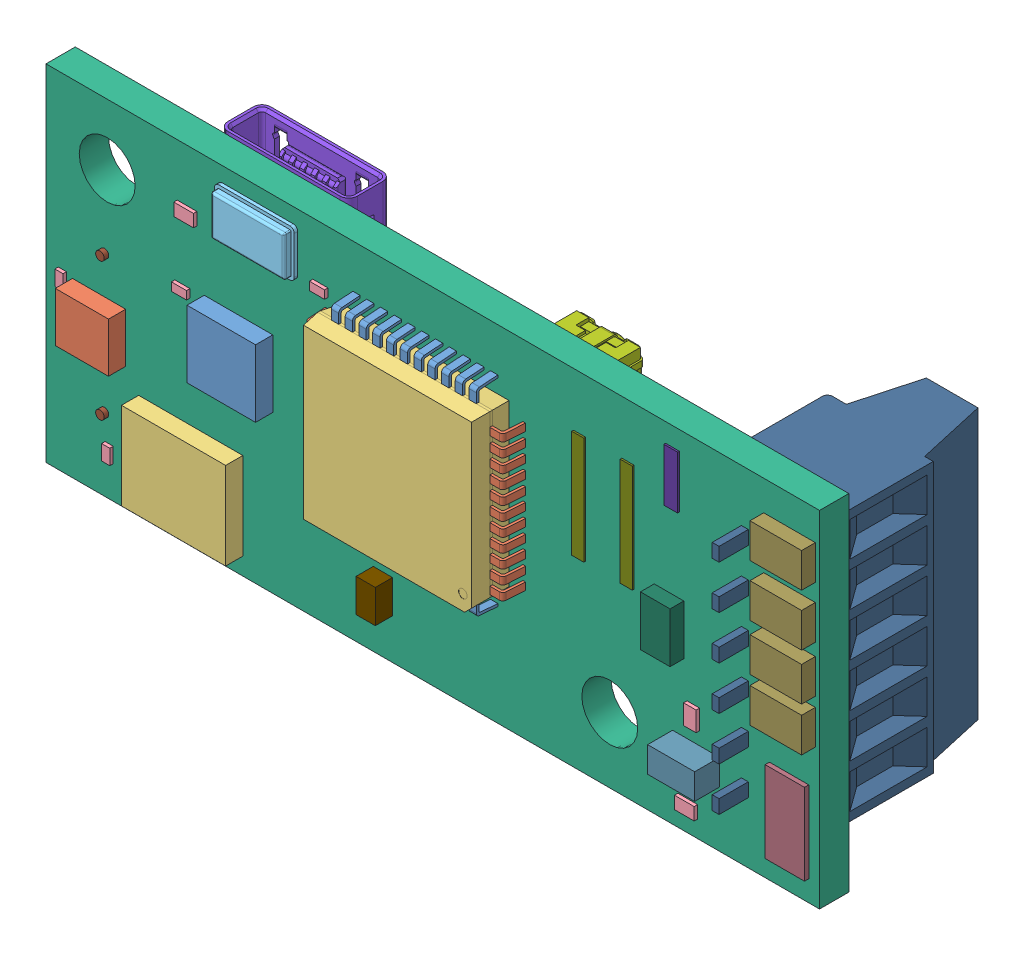
SolidWorks assembly Raven 4 v9.step, configuration Default. Lengths in mm.
Overall size (44.96 20.26 13.9).
79 component instances, 25 part files, 0 mates.
Components (placement in the parent):
- 44Q_PQFP_MODEL.step-1: 44Q_PQFP_MODEL.step [Default] at (23.3145 33.6577 9.414) x (0 1 0) z (1 0 0) size (13.2 2.45 13.2)
  - 44Q_PIN23.step-1: 44Q_PIN23.step [Default] at (-26.9483 -6.4622 -3.4548) x (-1 0 0) z (0 0 -1) size (1.8 1.5 0.42)
  - 44Q_PIN44.step-1: 44Q_PIN44.step [Default] at (-24.9358 -6.4622 3.7327) x (-1 0 0) z (0 0 -1) size (0.42 1.5 1.8)
  - 44Q_PIN23.step-2: 44Q_PIN23.step [Default] at (-26.9483 -6.4622 -5.0548) x (-1 0 0) z (0 0 -1) size (1.8 1.5 0.42)
  - 44Q_PIN23.step-3: 44Q_PIN23.step [Default] at (-26.9483 -6.4622 -1.0548) x (-1 0 0) z (0 0 -1) size (1.8 1.5 0.42)
  - 44Q_TQFP_BODY.step-1: 44Q_TQFP_BODY.step [Default] at (-26.9483 -6.6122 3.7327) size (10 2.2 10)
  - 44Q_PIN44.step-2: 44Q_PIN44.step [Default] at (-23.3358 -6.4622 3.7327) x (-1 0 0) z (0 0 -1) size (0.42 1.5 1.8)
  - 44Q_PIN23.step-4: 44Q_PIN23.step [Default] at (-26.9483 -6.4622 2.1452) x (-1 0 0) z (0 0 -1) size (1.8 1.5 0.42)
  - 44Q_PIN44.step-3: 44Q_PIN44.step [Default] at (-24.5608 -6.4622 -6.2673) size (0.42 1.5 1.8)
  - 44Q_PIN23.step-5: 44Q_PIN23.step [Default] at (-16.9483 -6.4622 -2.2798) size (1.8 1.5 0.42)
  - 44Q_PIN23.step-6: 44Q_PIN23.step [Default] at (-16.9483 -6.4622 -4.6798) size (1.8 1.5 0.42)
  - 44Q_PIN44.step-4: 44Q_PIN44.step [Default] at (-25.7358 -6.4622 3.7327) x (-1 0 0) z (0 0 -1) size (0.42 1.5 1.8)
  - 44Q_PIN23.step-7: 44Q_PIN23.step [Default] at (-26.9483 -6.4622 2.9452) x (-1 0 0) z (0 0 -1) size (1.8 1.5 0.42)
  - 44Q_PIN44.step-5: 44Q_PIN44.step [Default] at (-19.3358 -6.4622 3.7327) x (-1 0 0) z (0 0 -1) size (0.42 1.5 1.8)
  - 44Q_PIN44.step-6: 44Q_PIN44.step [Default] at (-25.3608 -6.4622 -6.2673) size (0.42 1.5 1.8)
  - 44Q_PIN23.step-8: 44Q_PIN23.step [Default] at (-26.9483 -6.4622 1.3452) x (-1 0 0) z (0 0 -1) size (1.8 1.5 0.42)
  - 44Q_PIN44.step-7: 44Q_PIN44.step [Default] at (-21.3608 -6.4622 -6.2673) size (0.42 1.5 1.8)
  - 44Q_PIN23.step-9: 44Q_PIN23.step [Default] at (-26.9483 -6.4622 0.5452) x (-1 0 0) z (0 0 -1) size (1.8 1.5 0.42)
  - 44Q_PIN23.step-10: 44Q_PIN23.step [Default] at (-16.9483 -6.4622 0.9202) size (1.8 1.5 0.42)
  - 44Q_PIN44.step-8: 44Q_PIN44.step [Default] at (-21.7358 -6.4622 3.7327) x (-1 0 0) z (0 0 -1) size (0.42 1.5 1.8)
  - 44Q_PIN44.step-9: 44Q_PIN44.step [Default] at (-22.5358 -6.4622 3.7327) x (-1 0 0) z (0 0 -1) size (0.42 1.5 1.8)
  - 44Q_PIN23.step-11: 44Q_PIN23.step [Default] at (-16.9483 -6.4622 -3.8798) size (1.8 1.5 0.42)
  - 44Q_PIN23.step-12: 44Q_PIN23.step [Default] at (-16.9483 -6.4622 1.7202) size (1.8 1.5 0.42)
  - 44Q_PIN44.step-10: 44Q_PIN44.step [Default] at (-17.7358 -6.4622 3.7327) x (-1 0 0) z (0 0 -1) size (0.42 1.5 1.8)
  - 44Q_PIN23.step-13: 44Q_PIN23.step [Default] at (-16.9483 -6.4622 -3.0798) size (1.8 1.5 0.42)
  - 44Q_PIN44.step-11: 44Q_PIN44.step [Default] at (-20.1358 -6.4622 3.7327) x (-1 0 0) z (0 0 -1) size (0.42 1.5 1.8)
  - 44Q_PIN44.step-12: 44Q_PIN44.step [Default] at (-20.9358 -6.4622 3.7327) x (-1 0 0) z (0 0 -1) size (0.42 1.5 1.8)
  - 44Q_PIN44.step-13: 44Q_PIN44.step [Default] at (-20.5608 -6.4622 -6.2673) size (0.42 1.5 1.8)
  - 44Q_PIN44.step-14: 44Q_PIN44.step [Default] at (-18.1608 -6.4622 -6.2673) size (0.42 1.5 1.8)
  - 44Q_PIN23.step-14: 44Q_PIN23.step [Default] at (-26.9483 -6.4622 -0.2548) x (-1 0 0) z (0 0 -1) size (1.8 1.5 0.42)
  - 44Q_PIN44.step-15: 44Q_PIN44.step [Default] at (-24.1358 -6.4622 3.7327) x (-1 0 0) z (0 0 -1) size (0.42 1.5 1.8)
  - 44Q_PIN23.step-15: 44Q_PIN23.step [Default] at (-26.9483 -6.4622 -2.6548) x (-1 0 0) z (0 0 -1) size (1.8 1.5 0.42)
  - 44Q_PIN44.step-16: 44Q_PIN44.step [Default] at (-26.1608 -6.4622 -6.2673) size (0.42 1.5 1.8)
  - 44Q_PIN23.step-16: 44Q_PIN23.step [Default] at (-16.9483 -6.4622 0.1202) size (1.8 1.5 0.42)
  - 44Q_PIN23.step-17: 44Q_PIN23.step [Default] at (-16.9483 -6.4622 -0.6798) size (1.8 1.5 0.42)
  - 44Q_PIN44.step-17: 44Q_PIN44.step [Default] at (-18.5358 -6.4622 3.7327) x (-1 0 0) z (0 0 -1) size (0.42 1.5 1.8)
  - 44Q_PIN44.step-18: 44Q_PIN44.step [Default] at (-19.7608 -6.4622 -6.2673) size (0.42 1.5 1.8)
  - 44Q_PIN44.step-19: 44Q_PIN44.step [Default] at (-23.7608 -6.4622 -6.2673) size (0.42 1.5 1.8)
  - 44Q_PIN44.step-20: 44Q_PIN44.step [Default] at (-22.1608 -6.4622 -6.2673) size (0.42 1.5 1.8)
  - 44Q_PIN23.step-18: 44Q_PIN23.step [Default] at (-26.9483 -6.4622 -1.8548) x (-1 0 0) z (0 0 -1) size (1.8 1.5 0.42)
  - 44Q_PIN23.step-19: 44Q_PIN23.step [Default] at (-26.9483 -6.4622 -4.2548) x (-1 0 0) z (0 0 -1) size (1.8 1.5 0.42)
  - 44Q_PIN23.step-20: 44Q_PIN23.step [Default] at (-16.9483 -6.4622 2.5202) size (1.8 1.5 0.42)
  - 44Q_PIN23.step-21: 44Q_PIN23.step [Default] at (-16.9483 -6.4622 -1.4798) size (1.8 1.5 0.42)
  - 44Q_PIN23.step-22: 44Q_PIN23.step [Default] at (-16.9483 -6.4622 -5.4798) size (1.8 1.5 0.42)
  - 44Q_PIN44.step-21: 44Q_PIN44.step [Default] at (-18.9608 -6.4622 -6.2673) size (0.42 1.5 1.8)
  - 44Q_PIN44.step-22: 44Q_PIN44.step [Default] at (-22.9608 -6.4622 -6.2673) size (0.42 1.5 1.8)
- 11.step-1: 11.step [Default] at origin size (7.14 6.74 0.61)
  - 13.step-1: 13.step [Default] at origin size (0.88 0.48 0.2)
  - 11-0.step-1: 11-0.step [Default] at origin size (4.64 2.72 0.61)
- PCB.step-1: PCB.step [Default] at origin size (44.96 20.07 1.7)
- TL6330AF200Q.step-1: TL6330AF200Q.step [Default] at (29.6968 18.666 0) x (1 0 0) z (0 0 -1) size (4.6 2.8 1.9)
- 2134536-2.step-1: 2134536-2.step [Default] at (12.1392 20.2602 -1.232) x (1 0 0) z (0 1 0) size (7.52 3.21 5)
- smt-1127-s-r.step-1: smt-1127-s-r.step [Default] at (24.3494 6.4643 0) x (1 0 0) z (0 0 -1) size (10.5 10.5 2.5)
- 282834-6--3DModel-STEP-1.step-1: 282834-6--3DModel-STEP-1.step [Default] at (43.8658 10.2856 -3) x (0 -1 0) z (1 0 0) size (15.7 13.4 6.5)
- Cap Electrolytic.step-1: Cap Electrolytic.step [Default] at (18.498 5.4796 -2.5) x (-1 0 0) z (0 0 -1) size (15.35 10.5 6.97)
- 1.step-1: 1.step [Default] at origin size (3 2 0.8)
- 1.step-2: 1.step [Default] at (0 -3.0152 0) size (3 2 0.8)
- 1.step-3: 1.step [Default] at (0 -5.7325 0) size (3 2 0.8)
- 1.step-4: 1.step [Default] at (0 -8.2919 0) size (3 2 0.8)
- 2.step-1: 2.step [Default] at origin size (2.28 4.73 0.25)
- 3.step-1: 3.step [Default] at origin size (2.73 1.49 1.45)
- 4.step-1: 4.step [Default] at origin size (1.72 2.91 0.8)
- 5.step-1: 5.step [Default] at origin size (0.7 6.25 0.1)
- 6.step-1: 6.step [Default] at origin size (0.8 3.07 0.1)
- 5.step-2: 5.step [Default] at (2.8145 0 0) size (0.7 6.25 0.1)
- 7.step-1: 7.step [Default] at origin size (1.12 1.93 1)
- 8.step-1: 8.step [Default] at origin size (3.98 3.91 1)
- 9.step-1: 9.step [Default] at origin size (3.09 2.88 1)
- 10.step-1: 10.step [Default] at origin size (6.05 5.07 1)
- 12.step-1: 12.step [Default] at origin size (1.15 0.73 0.2)
- 12.step-2: 12.step [Default] at (29.1012 -15.3045 0) size (1.15 0.73 0.2)
- 12.step-3: 12.step [Default] at (54.2758 -2.1408 0) x (0 1 0) z (0 0 1) size (1.15 0.73 0.2)
- 13.step-1: 13.step [Default] at (13.6501 1.8292 0) x (0 1 0) z (0 0 1) size (0.88 0.48 0.2)
- 13.step-2: 13.step [Default] at (16.3666 -5.5969 0) x (0 1 0) z (0 0 1) size (0.88 0.48 0.2)
- 13.step-3: 13.step [Default] at (8.0207 4.0459 0) size (0.88 0.48 0.2)
- 14.step-1: 14.step [Default] at origin size (1.93 1.32 1.2)
- 15.step-1: 15.step [Default] at origin size (1.18 0.79 0.5)
- 16.step-1: 16.step [Default] at origin size (1.09 0.7 0.3)
- 15.step-2: 15.step [Default] at (17.4665 19.2582 0) x (0 -1 0) z (0 0 1) size (1.18 0.79 0.5)
